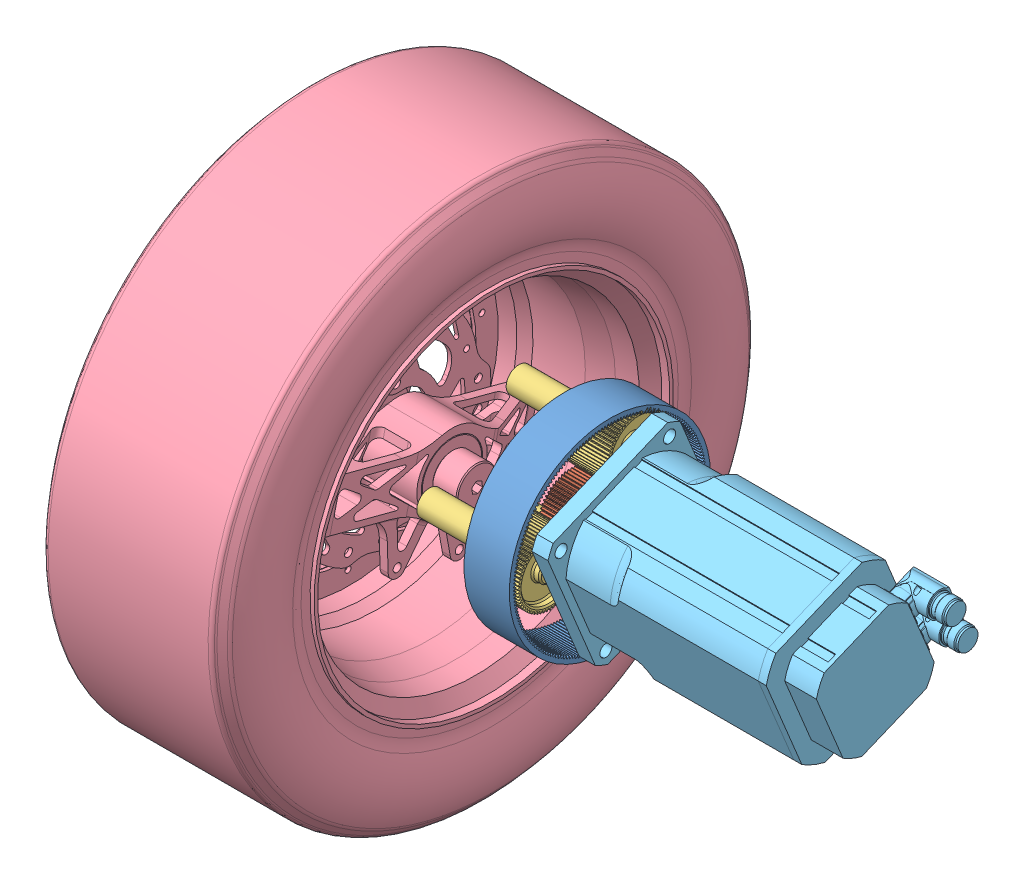
SolidWorks assembly In-wheel-Motor-with-tranmission, configuration Default. Lengths in mm.
Overall size (587.86 627.92 627.92).
7 component instances, 5 part files, 8 mates.
Components (placement in the parent):
- Ring Gear-1: Ring Gear [Default] at (-226.3595 280.2634 106.6257) x (-1 0 0) z (0 -0.924225 -0.381849) size (45 200 200)
- Sun Gear Final-1: Sun Gear Final [Default] at (-158.1794 279.9322 143.7397) x (-1 0 0) z (0 -0.924225 -0.381849) size (50 64.97 64.99)
- Planet-1: Planet [Default] at (-208.0407 198.0224 68.27) size (120 64.97 64.99)
- Planet-2: Planet [Default] at (-208.0407 318.0877 73.7534) size (120 64.97 64.99)
- Planet-3: Planet [Default] at (-208.0407 256.4096 162.5484) size (120 64.97 64.99)
- Wheel-1: Wheel [Default] at (-150.2981 172.5738 135.1103) x (0 0.982373 -0.186931) z (1 0 0) size (537 537 198.76)
- TGN5-1600-KE1 (2)-2: TGN5-1600-KE1 (2) [Default] at (-37.0147 299.2998 94.5573) x (0 -0.924225 -0.381849) z (1 0 0) size (142 152 325.19)
Mates (geometry in assembly coordinates):
- Distance1: distance = 0 mm aligned: plane of Sun Gear Final-1 through (-233.4155 263.1125 96.9876) normal (-1 0 0); plane of Ring Gear-1 through (-233.4155 350.4062 138.4386) normal (-1 0 0)
- Distance2: distance = 0 mm aligned: plane of Ring Gear-1 through (-233.4155 350.4062 138.4386) normal (-1 0 0); plane of Planet-1 through (-233.4155 202.8098 67.8625) normal (-1 0 0)
- Distance4: distance = 0 mm aligned: plane of Ring Gear-1 through (-233.4155 350.4062 138.4386) normal (-1 0 0); plane of Planet-2 through (-233.4155 322.875 73.346) normal (-1 0 0)
- Distance6: distance = 0 mm aligned: plane of Planet-3 through (-233.4155 261.1969 162.1409) normal (-1 0 0); plane of Ring Gear-1 through (-233.4155 350.4062 138.4386) normal (-1 0 0)
- Parallel4: parallel anti-aligned: plane of Ring Gear-1 through (-233.4155 350.4062 138.4386) normal (-1 0 0); plane of Wheel-1 through (-318.4211 240.4061 104.6967) normal (1 0 0)
- Distance8: distance = 0 mm: plane of Sun Gear Final-1 through (-233.4155 263.1125 96.9876) normal (-1 0 0); plane of TGN5-1600-KE1 (2)-2 through (-233.4155 263.4562 96.1558) normal (-1 0 0)
- Distance7: distance = 0 mm: plane of TGN5-1600-KE1 (2)-2 through (-208.4155 270.1697 90.3818) normal (0 0.924225 0.381849); plane of Sun Gear Final-1 through (-238.4155 272.8426 83.9122) normal (0 -0.924225 -0.381849)
- Distance9: distance = 0 mm: plane of Sun Gear Final-1 through (-238.4155 265.4488 80.8574) normal (0 -0.381849 0.924225); plane of TGN5-1600-KE1 (2)-2 through (-208.4155 269.1457 82.3848) normal (0 0.381849 -0.924225)
